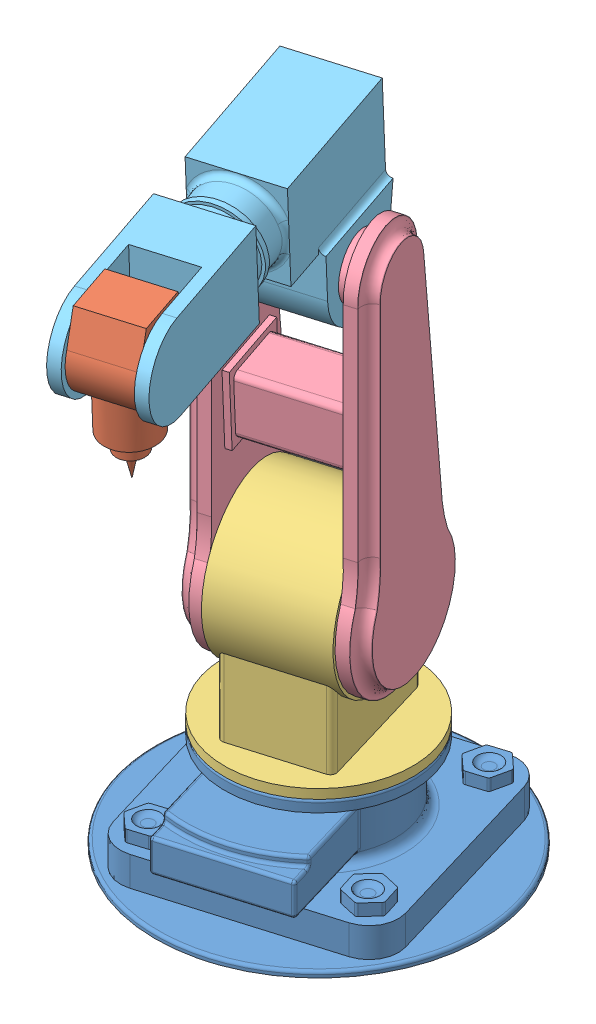
SolidWorks assembly Robot, configuration Default. Lengths in mm.
Overall size (690.33 1118.84 1413.92).
5 component instances, 5 part files, 12 mates.
Components (placement in the parent):
- Part1-1: Part1 [Default] at (316.6481 -360.8028 856.6841) x (0.958398 0 -0.285437) z (0.285437 0 0.958398) size (555 180 555)
- Part5-1: Part5 [Default] at (439.7618 652.5236 1305.0911) x (-0.016821 -0.998262 -0.05648) z (-0.958398 0 0.285437) size (275 130 100)
- Part2-1: Part2 [Default] at (316.6481 -300.8028 856.6841) x (0.285437 0 0.958398) z (-0.958398 0 0.285437) size (320 466 320)
- Part3-3: Part3 [Default] at (316.5729 30.7314 856.4314) x (0.284941 -0.058932 0.956732) z (-0.016821 -0.998262 -0.05648) size (250 260.14 700)
- Part4-1: Part4 [Default] at (291.5926 683.1683 807.5906) x (0.284941 -0.058932 0.956732) z (-0.958398 0 0.285437) size (595 296.15 160)
Mates (geometry in assembly coordinates):
- Concentric1: concentric anti-aligned: cylinder of Part1-1 through (316.6481 -280.8028 856.6841) axis (0 1 0) radius 100; cylinder of Part2-1 through (316.6481 -180.8028 856.6841) axis (0 -1 0) radius 100
- Coincident1: coincident anti-aligned: plane of Part1-1 through (316.6481 -180.8028 856.6841) normal (0 1 0); plane of Part2-1 through (316.6481 -180.8028 856.6841) normal (0 -1 0)
- Concentric2: concentric aligned: cylinder of Part2-1 through (230.3923 35.1972 882.3734) axis (0.958398 0 -0.285437) radius 75; cylinder of Part3-3 through (230.3923 35.1972 882.3734) axis (0.958398 0 -0.285437) radius 75
- Coincident2: coincident anti-aligned: plane of Part2-1 through (230.3923 35.1972 882.3734) normal (-0.958398 0 0.285437); plane of Part3-3 through (238.803 534.3282 910.6135) normal (0.958398 0 -0.285437)
- Concentric3: concentric aligned: cylinder of Part3-3 through (238.803 534.3282 910.6135) axis (0.958398 0 -0.285437) radius 50; cylinder of Part4-1 through (238.803 534.3282 910.6135) axis (0.958398 0 -0.285437) radius 50
- Coincident3: coincident anti-aligned: plane of Part3-3 through (238.803 534.3282 910.6135) normal (0.958398 0 -0.285437); plane of Part4-1 through (238.803 534.3282 910.6135) normal (-0.958398 0 0.285437)
- Concentric4: concentric aligned: cylinder of Part4-1 through (391.842 652.5236 1319.363) axis (0.958398 0 -0.285437) radius 50; cylinder of Part5-1 through (391.842 652.5236 1319.363) axis (0.958398 0 -0.285437) radius 50
- Coincident4: coincident anti-aligned: plane of Part4-1 through (391.842 652.5236 1319.363) normal (0.958398 0 -0.285437); plane of Part5-1 through (391.842 652.5236 1319.363) normal (-0.958398 0 0.285437)
- Parallel1: parallel aligned: plane of Part1-1 through (451.2402 -300.8028 607.9172) normal (0.958398 0 -0.285437); plane of Part2-1 through (361.9218 165.1992 728.4254) normal (0.958398 0 -0.285437)
- Parallel3: parallel aligned: line of Part2-1 through (415.134 -164.8028 942.1272) axis (0 1 0); line of Part3-3 through (451.5676 156.7957 924.3227) axis (0 1 0)
- Perpendicular2: perpendicular: plane of Part3-3 through (209.6099 247.468 952.7362) normal (0.284941 -0.058932 0.956732); plane of Part4-1 through (371.4124 577.654 1320.8357) normal (-0.016821 -0.998262 -0.05648)
- Parallel6: parallel aligned: plane of Part5-1 through (381.79 734.7419 1285.6121) normal (0.016821 0.998262 0.05648); plane of Part4-1 through (316.9475 739.1797 1137.9614) normal (0.016821 0.998262 0.05648)
